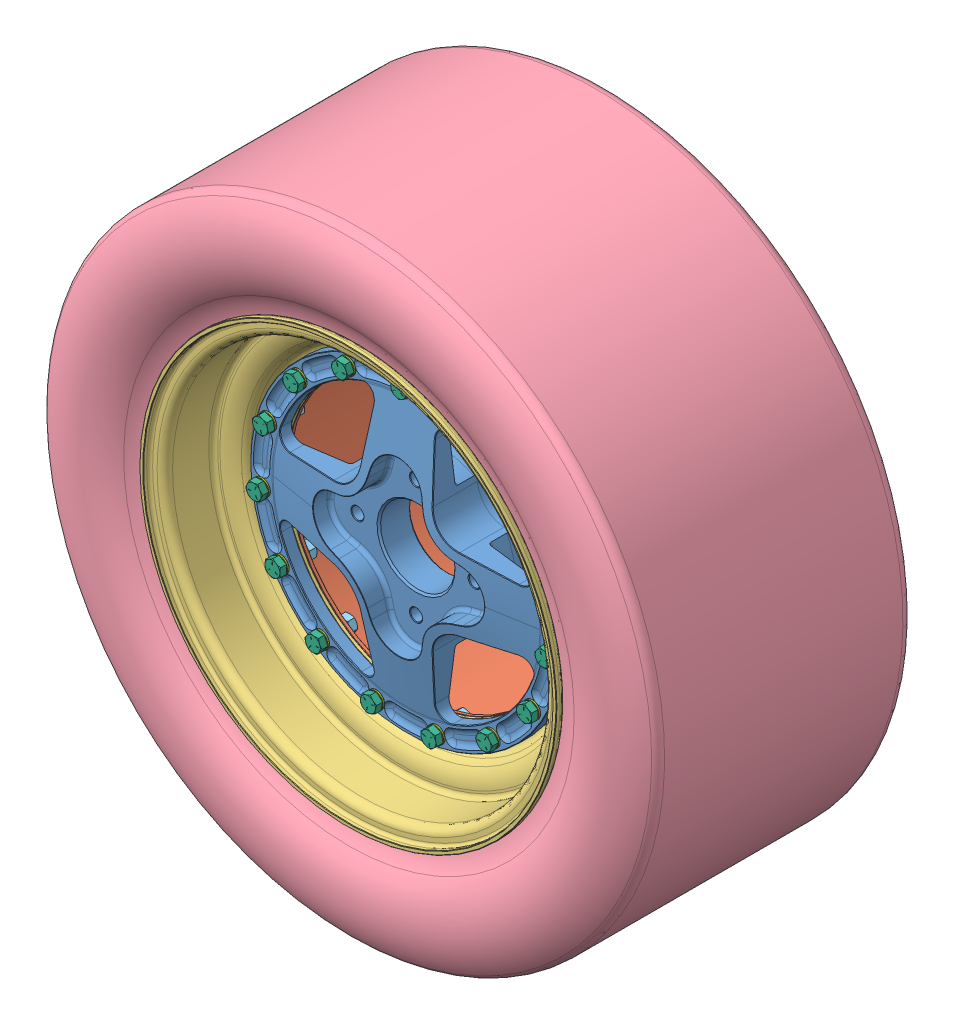
SolidWorks assembly Rear Wheel, configuration Default. Lengths in mm.
Overall size (523.24 523.24 238.76).
64 component instances, 7 part files, 17 mates.
Components (placement in the parent):
- Rear Center-1: Rear Center [Default] at origin size (266.7 266.7 48.96)
- Rear Inner Rim-1: Rear Inner Rim [Default] at (0 0 -31.75) x (0 0 -1) z (1 0 0) size (160.02 355.6 355.6)
- Rear Outer Rim-1: Rear Outer Rim [Default] at (0 0 -31.75) size (355.6 355.6 62.86)
- Rear Tire-1: Rear Tire [Default] at (0 0 -78.994) x (0 0 1) z (-1 0 0) size (238.76 523.24 523.24)
- Steel Hex 5_16-18 Grade 5-1: Steel Hex 5_16-18 Grade 5 [95462A030] at (0 123.825 -40.0129) size (12.7 14.66 8.63)
- Steel Hex 5_16in-18 1in Grade 5-1: Steel Hex 5_16in-18 1in Grade 5 [92865A583] at (0 123.825 -27.2574) x (0 0 -1) z (1 0 0) size (31.64 14.66 12.7)
- 5_16 Small OD Washer-1: 5_16 Small OD Washer [Default] at (0 123.825 -19.05) x (1 0 0) z (0 -1 0) size (14.22 1.72 14.22)
- 5_16 Small OD Washer-2: 5_16 Small OD Washer [Default] at (0 123.825 -36.6395) x (1 0 0) z (0 -1 0) size (14.22 1.72 14.22)
- 5_16 Small OD Washer-3: 5_16 Small OD Washer [Default] at (50.3642 113.1198 -36.6395) x (0.913545 -0.406737 0) z (-0.406737 -0.913545 0) size (14.22 1.72 14.22)
- 5_16 Small OD Washer-4: 5_16 Small OD Washer [Default] at (92.0199 82.8551 -36.6395) x (0.669131 -0.743145 0) z (-0.743145 -0.669131 0) size (14.22 1.72 14.22)
- 5_16 Small OD Washer-5: 5_16 Small OD Washer [Default] at (117.7646 38.264 -36.6395) x (0.309017 -0.951057 0) z (-0.951057 -0.309017 0) size (14.22 1.72 14.22)
- 5_16 Small OD Washer-6: 5_16 Small OD Washer [Default] at (123.1467 -12.9432 -36.6395) x (-0.104528 -0.994522 0) z (-0.994522 0.104528 0) size (14.22 1.72 14.22)
- 5_16 Small OD Washer-7: 5_16 Small OD Washer [Default] at (107.2356 -61.9125 -36.6395) x (-0.5 -0.866025 0) z (-0.866025 0.5 0) size (14.22 1.72 14.22)
- 5_16 Small OD Washer-8: 5_16 Small OD Washer [Default] at (72.7825 -100.1765 -36.6395) x (-0.809017 -0.587785 0) z (-0.587785 0.809017 0) size (14.22 1.72 14.22)
- 5_16 Small OD Washer-9: 5_16 Small OD Washer [Default] at (25.7447 -121.1191 -36.6395) x (-0.978148 -0.207912 0) z (-0.207912 0.978148 0) size (14.22 1.72 14.22)
- 5_16 Small OD Washer-10: 5_16 Small OD Washer [Default] at (-25.7447 -121.1191 -36.6395) x (-0.978148 0.207912 0) z (0.207912 0.978148 0) size (14.22 1.72 14.22)
- 5_16 Small OD Washer-11: 5_16 Small OD Washer [Default] at (-72.7825 -100.1765 -36.6395) x (-0.809017 0.587785 0) z (0.587785 0.809017 0) size (14.22 1.72 14.22)
- 5_16 Small OD Washer-12: 5_16 Small OD Washer [Default] at (-107.2356 -61.9125 -36.6395) x (-0.5 0.866025 0) z (0.866025 0.5 0) size (14.22 1.72 14.22)
- 5_16 Small OD Washer-13: 5_16 Small OD Washer [Default] at (-123.1467 -12.9432 -36.6395) x (-0.104528 0.994522 0) z (0.994522 0.104528 0) size (14.22 1.72 14.22)
- 5_16 Small OD Washer-14: 5_16 Small OD Washer [Default] at (-117.7646 38.264 -36.6395) x (0.309017 0.951057 0) z (0.951057 -0.309017 0) size (14.22 1.72 14.22)
- 5_16 Small OD Washer-15: 5_16 Small OD Washer [Default] at (-92.0199 82.8551 -36.6395) x (0.669131 0.743145 0) z (0.743145 -0.669131 0) size (14.22 1.72 14.22)
- 5_16 Small OD Washer-16: 5_16 Small OD Washer [Default] at (-50.3642 113.1198 -36.6395) x (0.913545 0.406737 0) z (0.406737 -0.913545 0) size (14.22 1.72 14.22)
- 5_16 Small OD Washer-17: 5_16 Small OD Washer [Default] at (50.3642 113.1198 -19.05) x (0.913545 -0.406737 0) z (-0.406737 -0.913545 0) size (14.22 1.72 14.22)
- 5_16 Small OD Washer-18: 5_16 Small OD Washer [Default] at (92.0199 82.8551 -19.05) x (0.669131 -0.743145 0) z (-0.743145 -0.669131 0) size (14.22 1.72 14.22)
- 5_16 Small OD Washer-19: 5_16 Small OD Washer [Default] at (117.7646 38.264 -19.05) x (0.309017 -0.951057 0) z (-0.951057 -0.309017 0) size (14.22 1.72 14.22)
- 5_16 Small OD Washer-20: 5_16 Small OD Washer [Default] at (123.1467 -12.9432 -19.05) x (-0.104528 -0.994522 0) z (-0.994522 0.104528 0) size (14.22 1.72 14.22)
- 5_16 Small OD Washer-21: 5_16 Small OD Washer [Default] at (107.2356 -61.9125 -19.05) x (-0.5 -0.866025 0) z (-0.866025 0.5 0) size (14.22 1.72 14.22)
- 5_16 Small OD Washer-22: 5_16 Small OD Washer [Default] at (72.7825 -100.1765 -19.05) x (-0.809017 -0.587785 0) z (-0.587785 0.809017 0) size (14.22 1.72 14.22)
- 5_16 Small OD Washer-23: 5_16 Small OD Washer [Default] at (25.7447 -121.1191 -19.05) x (-0.978148 -0.207912 0) z (-0.207912 0.978148 0) size (14.22 1.72 14.22)
- 5_16 Small OD Washer-24: 5_16 Small OD Washer [Default] at (-25.7447 -121.1191 -19.05) x (-0.978148 0.207912 0) z (0.207912 0.978148 0) size (14.22 1.72 14.22)
- 5_16 Small OD Washer-25: 5_16 Small OD Washer [Default] at (-72.7825 -100.1765 -19.05) x (-0.809017 0.587785 0) z (0.587785 0.809017 0) size (14.22 1.72 14.22)
- 5_16 Small OD Washer-26: 5_16 Small OD Washer [Default] at (-107.2356 -61.9125 -19.05) x (-0.5 0.866025 0) z (0.866025 0.5 0) size (14.22 1.72 14.22)
- 5_16 Small OD Washer-27: 5_16 Small OD Washer [Default] at (-123.1467 -12.9432 -19.05) x (-0.104528 0.994522 0) z (0.994522 0.104528 0) size (14.22 1.72 14.22)
- 5_16 Small OD Washer-28: 5_16 Small OD Washer [Default] at (-117.7646 38.264 -19.05) x (0.309017 0.951057 0) z (0.951057 -0.309017 0) size (14.22 1.72 14.22)
- 5_16 Small OD Washer-29: 5_16 Small OD Washer [Default] at (-92.0199 82.8551 -19.05) x (0.669131 0.743145 0) z (0.743145 -0.669131 0) size (14.22 1.72 14.22)
- 5_16 Small OD Washer-30: 5_16 Small OD Washer [Default] at (-50.3642 113.1198 -19.05) x (0.913545 0.406737 0) z (0.406737 -0.913545 0) size (14.22 1.72 14.22)
- Steel Hex 5_16in-18 1in Grade 5-2: Steel Hex 5_16in-18 1in Grade 5 [92865A583] at (50.3642 113.1198 -27.2574) x (0 0 -1) z (0.913545 -0.406737 0) size (31.64 14.66 12.7)
- Steel Hex 5_16in-18 1in Grade 5-3: Steel Hex 5_16in-18 1in Grade 5 [92865A583] at (92.0199 82.8551 -27.2574) x (0 0 -1) z (0.669131 -0.743145 0) size (31.64 14.66 12.7)
- Steel Hex 5_16in-18 1in Grade 5-4: Steel Hex 5_16in-18 1in Grade 5 [92865A583] at (117.7646 38.264 -27.2574) x (0 0 -1) z (0.309017 -0.951057 0) size (31.64 14.66 12.7)
- Steel Hex 5_16in-18 1in Grade 5-5: Steel Hex 5_16in-18 1in Grade 5 [92865A583] at (123.1467 -12.9432 -27.2574) x (0 0 -1) z (-0.104528 -0.994522 0) size (31.64 14.66 12.7)
- Steel Hex 5_16in-18 1in Grade 5-6: Steel Hex 5_16in-18 1in Grade 5 [92865A583] at (107.2356 -61.9125 -27.2574) x (0 0 -1) z (-0.5 -0.866025 0) size (31.64 14.66 12.7)
- Steel Hex 5_16in-18 1in Grade 5-7: Steel Hex 5_16in-18 1in Grade 5 [92865A583] at (72.7825 -100.1765 -27.2574) x (0 0 -1) z (-0.809017 -0.587785 0) size (31.64 14.66 12.7)
- Steel Hex 5_16in-18 1in Grade 5-8: Steel Hex 5_16in-18 1in Grade 5 [92865A583] at (25.7447 -121.1191 -27.2574) x (0 0 -1) z (-0.978148 -0.207912 0) size (31.64 14.66 12.7)
- Steel Hex 5_16in-18 1in Grade 5-9: Steel Hex 5_16in-18 1in Grade 5 [92865A583] at (-25.7447 -121.1191 -27.2574) x (0 0 -1) z (-0.978148 0.207912 0) size (31.64 14.66 12.7)
- Steel Hex 5_16in-18 1in Grade 5-10: Steel Hex 5_16in-18 1in Grade 5 [92865A583] at (-72.7825 -100.1765 -27.2574) x (0 0 -1) z (-0.809017 0.587785 0) size (31.64 14.66 12.7)
- Steel Hex 5_16in-18 1in Grade 5-11: Steel Hex 5_16in-18 1in Grade 5 [92865A583] at (-107.2356 -61.9125 -27.2574) x (0 0 -1) z (-0.5 0.866025 0) size (31.64 14.66 12.7)
- Steel Hex 5_16in-18 1in Grade 5-12: Steel Hex 5_16in-18 1in Grade 5 [92865A583] at (-123.1467 -12.9432 -27.2574) x (0 0 -1) z (-0.104528 0.994522 0) size (31.64 14.66 12.7)
- Steel Hex 5_16in-18 1in Grade 5-13: Steel Hex 5_16in-18 1in Grade 5 [92865A583] at (-117.7646 38.264 -27.2574) x (0 0 -1) z (0.309017 0.951057 0) size (31.64 14.66 12.7)
- Steel Hex 5_16in-18 1in Grade 5-14: Steel Hex 5_16in-18 1in Grade 5 [92865A583] at (-92.0199 82.8551 -27.2574) x (0 0 -1) z (0.669131 0.743145 0) size (31.64 14.66 12.7)
- Steel Hex 5_16in-18 1in Grade 5-15: Steel Hex 5_16in-18 1in Grade 5 [92865A583] at (-50.3642 113.1198 -27.2574) x (0 0 -1) z (0.913545 0.406737 0) size (31.64 14.66 12.7)
- Steel Hex 5_16-18 Grade 5-2: Steel Hex 5_16-18 Grade 5 [95462A030] at (50.3642 113.1198 -40.0129) x (0.913545 -0.406737 0) z (0 0 1) size (12.7 14.66 8.63)
- Steel Hex 5_16-18 Grade 5-3: Steel Hex 5_16-18 Grade 5 [95462A030] at (92.0199 82.8551 -40.0129) x (0.669131 -0.743145 0) z (0 0 1) size (12.7 14.66 8.63)
- Steel Hex 5_16-18 Grade 5-4: Steel Hex 5_16-18 Grade 5 [95462A030] at (117.7646 38.264 -40.0129) x (0.309017 -0.951057 0) z (0 0 1) size (12.7 14.66 8.63)
- Steel Hex 5_16-18 Grade 5-5: Steel Hex 5_16-18 Grade 5 [95462A030] at (123.1467 -12.9432 -40.0129) x (-0.104528 -0.994522 0) z (0 0 1) size (12.7 14.66 8.63)
- Steel Hex 5_16-18 Grade 5-6: Steel Hex 5_16-18 Grade 5 [95462A030] at (107.2356 -61.9125 -40.0129) x (-0.5 -0.866025 0) z (0 0 1) size (12.7 14.66 8.63)
- Steel Hex 5_16-18 Grade 5-7: Steel Hex 5_16-18 Grade 5 [95462A030] at (72.7825 -100.1765 -40.0129) x (-0.809017 -0.587785 0) z (0 0 1) size (12.7 14.66 8.63)
- Steel Hex 5_16-18 Grade 5-8: Steel Hex 5_16-18 Grade 5 [95462A030] at (25.7447 -121.1191 -40.0129) x (-0.978148 -0.207912 0) z (0 0 1) size (12.7 14.66 8.63)
- Steel Hex 5_16-18 Grade 5-9: Steel Hex 5_16-18 Grade 5 [95462A030] at (-25.7447 -121.1191 -40.0129) x (-0.978148 0.207912 0) z (0 0 1) size (12.7 14.66 8.63)
- Steel Hex 5_16-18 Grade 5-10: Steel Hex 5_16-18 Grade 5 [95462A030] at (-72.7825 -100.1765 -40.0129) x (-0.809017 0.587785 0) z (0 0 1) size (12.7 14.66 8.63)
- Steel Hex 5_16-18 Grade 5-11: Steel Hex 5_16-18 Grade 5 [95462A030] at (-107.2356 -61.9125 -40.0129) x (-0.5 0.866025 0) z (0 0 1) size (12.7 14.66 8.63)
- Steel Hex 5_16-18 Grade 5-12: Steel Hex 5_16-18 Grade 5 [95462A030] at (-123.1467 -12.9432 -40.0129) x (-0.104528 0.994522 0) z (0 0 1) size (12.7 14.66 8.63)
- Steel Hex 5_16-18 Grade 5-13: Steel Hex 5_16-18 Grade 5 [95462A030] at (-117.7646 38.264 -40.0129) x (0.309017 0.951057 0) z (0 0 1) size (12.7 14.66 8.63)
- Steel Hex 5_16-18 Grade 5-14: Steel Hex 5_16-18 Grade 5 [95462A030] at (-92.0199 82.8551 -40.0129) x (0.669131 0.743145 0) z (0 0 1) size (12.7 14.66 8.63)
- Steel Hex 5_16-18 Grade 5-15: Steel Hex 5_16-18 Grade 5 [95462A030] at (-50.3642 113.1198 -40.0129) x (0.913545 0.406737 0) z (0 0 1) size (12.7 14.66 8.63)
Mates (geometry in assembly coordinates):
- Coincident1: coordinate: point of Rear Center-1; point of assembly
- Concentric2: concentric anti-aligned: cylinder of Rear Inner Rim-1 through (0 0 -25.019) axis (0 0 1) radius 162.6489; cylinder of Rear Outer Rim-1 through (0 0 -33.6231) axis (0 0 -1) radius 164.8473
- Coincident3: coincident anti-aligned: plane of Rear Inner Rim-1 through (0 114.3 -31.75) normal (0 0 1); plane of Rear Outer Rim-1 through (0 114.3 -31.75) normal (0 0 -1)
- Concentric3: concentric aligned: cylinder of Rear Inner Rim-1 through (92.0199 82.8551 -191.7706) axis (0 0 1) radius 4.4983; cylinder of Rear Outer Rim-1 through (92.0199 82.8551 -31.75) axis (0 0 1) radius 4.4983
- Coincident5: coincident anti-aligned: plane of Rear Center-1 through (134.5492 -134.5492 -28.575) normal (0 0 -1); plane of Rear Outer Rim-1 through (0 114.3 -28.575) normal (0 0 1)
- Concentric4: concentric anti-aligned: cylinder of Rear Center-1 through (0 0 -18.573) axis (0 0 -1) radius 133.35; cylinder of Rear Inner Rim-1 through (0 0 -25.019) axis (0 0 1) radius 162.6489
- Concentric5: concentric aligned: cylinder of Rear Center-1 through (0 123.825 -29.052) axis (0 0 1) radius 4.1021; cylinder of Rear Outer Rim-1 through (0 123.825 -31.75) axis (0 0 1) radius 4.4983
- Concentric6: concentric anti-aligned: cylinder of Rear Inner Rim-1 through (0 0 -25.019) axis (0 0 1) radius 162.6489; cylinder of Rear Tire-1 through (0 0 -102.1727) axis (0 0 -1) radius 261.62
- Distance1: distance = 24.384 mm anti-aligned: plane of Rear Tire-1 through (0 0 -78.994) normal (0 0 1); plane of Rear Center-1 through (0 0 -54.61) normal (0 0 -1)
- Coincident6: coincident anti-aligned: plane of Rear Inner Rim-1 through (0 114.3 -34.925) normal (0 0 -1); plane of 5_16 Small OD Washer-2 through (-6.9403 130.7653 -34.925) normal (0 0 1)
- Concentric7: concentric anti-aligned: cylinder of Rear Center-1 through (0 123.825 -29.052) axis (0 0 1) radius 4.1021; cylinder of 5_16 Small OD Washer-2 through (0 123.825 -35.0584) axis (0 0 -1) radius 4.064
- Concentric8: concentric anti-aligned: cylinder of Rear Center-1 through (0 123.825 -29.052) axis (0 0 1) radius 4.1021; circle of Steel Hex 5_16-18 Grade 5-1
- Coincident7: coincident anti-aligned: plane of Steel Hex 5_16-18 Grade 5-1 through (-6.35 127.4912 -36.6395) normal (0 0 1); plane of 5_16 Small OD Washer-2 through (-6.9403 130.7653 -36.6395) normal (0 0 -1)
- Coincident8: coincident anti-aligned: plane of Rear Center-1 through (-134.5492 -134.5492 -19.05) normal (0 0 1); plane of 5_16 Small OD Washer-1 through (-6.9403 130.7653 -19.05) normal (0 0 -1)
- Concentric9: concentric anti-aligned: cylinder of Rear Center-1 through (0 123.825 -29.052) axis (0 0 1) radius 4.1021; cylinder of 5_16 Small OD Washer-1 through (0 123.825 -17.4688) axis (0 0 -1) radius 4.064
- Concentric10: concentric anti-aligned: circle of Steel Hex 5_16in-18 1in Grade 5-1; cylinder of 5_16 Small OD Washer-1 through (0 123.825 -17.4688) axis (0 0 -1) radius 4.064
- Coincident9: coincident anti-aligned: plane of Steel Hex 5_16in-18 1in Grade 5-1 through (6.35 127.4912 -17.3355) normal (0 0 -1); plane of 5_16 Small OD Washer-1 through (-6.9403 130.7653 -17.3355) normal (0 0 1)
